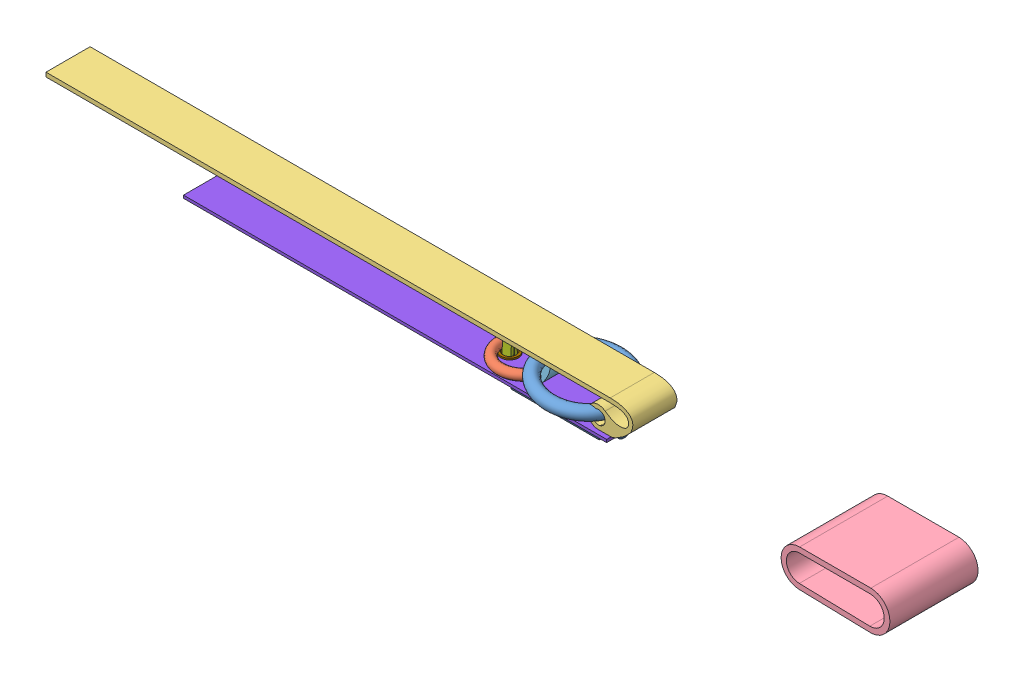
SolidWorks assembly 3-ring_assy_V1, configuration Default. Lengths in mm.
Overall size (289.62 40.67 53.79).
11 component instances, 10 part files, 25 mates.
Components (placement in the parent):
- H3860S_NO3_Ring-1: H3860S_NO3_Ring [Default] at (-68.6501 18.5376 22.2389) x (0 0 1) z (0.105483 0.994421 0) size (31.35 31.35 4.56)
- H3880S_NO4_Ring-1: H3880S_NO4_Ring [Default] at (-95.1677 16.38 22.2389) x (0 0 1) z (0 1 0) size (20.24 20.24 3.37)
- Webbing_mid-1: Webbing_mid [Default] at (-166.1457 26.6928 22.2389) x (1 0 0) z (0 0 -1) size (211.94 13.13 15.88)
- Webbing_main-1: Webbing_main [Default] x (-1 0 0) z (0 0 1) size (39.18 13.97 31.75)
- webbing_top_V1-2: webbing_top_V1 [Default] at (-133.3238 25.1688 22.2389) x (1 0 0) z (0 0 -1) size (81.41 11.51 12.7)
- yellow_cord_V1-1: yellow_cord_V1 [Default] at (-76.9625 11.3625 21.1309) x (0.034899 0 0.999391) z (0 -1 0) size (9.91 63.2 1.27)
- nylon_loop_V1-1: nylon_loop_V1 [Default] at (-108.6932 9.4219 22.2389) x (0 0 1) z (0 -1 0) size (3.01 25.4 13.88)
- grommet_assy-1: grommet_assy [Default] at (-244.1415 185.836 43.4745) x (0 0 -1) z (0 -1 0) size (19.05 152.4 6.48)
  - webbing_grommet_V1-1: webbing_grommet_V1 [Default] at (21.2356 27.4983 171.1427) size (19.05 152.4 1.02)
  - grommet_V1-1: grommet_V1 [Default] at (21.2356 135.4483 170.5712) x (1 0 0) z (0 -1 0) size (10.16 2.6 10.16)
  - yellow_cord_guide-1: yellow_cord_guide [Default] at (21.2356 176.7233 174.1907) x (1 0 0) z (0 -1 0) size (18.04 4.89 31.75)
Mates (geometry in assembly coordinates):
- Coincident65: coincident: plane of Webbing_main-1 through (0 0 0) normal (0 0 1); plane of assembly through (0 0 0) normal (0 0 1)
- Coincident66: coincident: plane of Webbing_main-1 through (0 0 0) normal (-1 0 0); plane of assembly through (0 0 0) normal (1 0 0)
- Coincident67: coincident: plane of Webbing_main-1 through (0 0 0) normal (0 -1 0); plane of assembly through (0 0 0) normal (0 1 0)
- Parallel29: parallel: plane of Webbing_mid-1 through (-166.1457 26.6928 22.2389) normal (0 1 0); plane of Webbing_main-1 through (0 0 0) normal (0 1 0)
- Parallel30: parallel: plane of Webbing_mid-1 through (-166.1457 26.6928 22.2389) normal (0 0 -1); plane of assembly through (0 0 0) normal (0 0 1)
- Coincident83: coincident: plane of Webbing_mid-1 through (-166.1457 25.1688 22.2389) normal (0 -1 0); plane of webbing_top_V1-2 through (-133.3238 25.1688 22.2389) normal (0 1 0)
- Parallel31: parallel: plane of Webbing_mid-1 through (-267.7457 25.1688 30.1764) normal (0 0 1); plane of webbing_top_V1-2 through (-171.4238 24.1528 28.5889) normal (0 0 1)
- Tangent33: tangent: torus of H3880S_NO4_Ring-1; plane of webbing_top_V1-2 through (-123.1879 -1.7048 0.0803) normal (0 -1 0)
- Angle1: planar angle = 0.034907 rad: cylinder of yellow_cord_V1-1 through (-127.7316 11.3625 22.9038) axis (0.999391 0 -0.034899) radius 0.635; cylinder of nylon_loop_V1-1 through (-107.1057 11.7068 22.2389) axis (-1 0 0) radius 0.762
- Parallel32: parallel: plane of H3880S_NO4_Ring-1 through (-95.1677 16.38 22.2389) normal (0 1 0); plane of assembly through (0 0 0) normal (0 1 0)
- Tangent35: tangent: torus of H3880S_NO4_Ring-1; cylinder of webbing_top_V1-2 through (-95.2238 16.5328 15.8889) axis (0 0 1) radius 1.524
- Tangent37: tangent: torus of H3860S_NO3_Ring-1; cylinder of webbing_top_V1-2 through (-95.2238 21.6128 15.8889) axis (0 0 1) radius 2.54
- Coincident84: coincident: plane of H3880S_NO4_Ring-1 through (-95.1677 16.38 22.2389) normal (0 0 1); plane of webbing_top_V1-2 through (-133.3238 25.1688 22.2389) normal (0 0 -1)
- Coincident85: coincident: plane of Webbing_mid-1 through (-166.1457 26.6928 22.2389) normal (0 0 -1); plane of webbing_top_V1-2 through (-133.3238 25.1688 22.2389) normal (0 0 -1)
- Coincident86: coincident: plane of H3860S_NO3_Ring-1 through (-68.6501 18.5376 22.2389) normal (0 0 1); plane of H3880S_NO4_Ring-1 through (-95.1677 16.38 22.2389) normal (0 0 1)
- Tangent38: tangent: torus of H3860S_NO3_Ring-1; cylinder of Webbing_mid-1 through (-68.7807 18.5474 30.1764) axis (0 0 -1) radius 2.413
- Parallel34: parallel: plane of webbing_top_V1-2 through (-133.3238 24.1528 22.2389) normal (0 -1 0); plane of grommet_assy-1/webbing_grommet_V1-1 through (-194.8149 13.6773 19.4353) normal (0 -1 0)
- Coincident91: coincident: plane of webbing_top_V1-2 through (-133.3238 24.1528 22.2389) normal (0 -1 0); plane of nylon_loop_V1-1 through (-108.6932 24.1528 23.1347) normal (0 1 0)
- Coincident92: coincident: plane of Webbing_mid-1 through (-166.1457 26.6928 22.2389) normal (0 0 -1); plane of nylon_loop_V1-1 through (-108.6932 9.4219 22.2389) normal (0 0 1)
- Coincident93: coincident: plane of H3880S_NO4_Ring-1 through (-110.2807 16.38 22.2389) normal (1 0 0); plane of nylon_loop_V1-1 through (-110.2807 9.4219 22.2389) normal (-1 0 0)
- Coincident95: coincident: line of yellow_cord_V1-1 through (-127.7316 11.3625 22.9038) axis (0.999391 0 -0.034899); point of nylon_loop_V1-1
- Distance1: distance = 31.75 mm: point of nylon_loop_V1-1; plane of yellow_cord_V1-1 through (-76.9625 11.3625 21.1309) normal (0.999391 0 -0.034899)
- Parallel35: parallel: plane of webbing_top_V1-2 through (-133.3238 24.1528 22.2389) normal (0 -1 0); plane of yellow_cord_V1-1 through (-76.9625 10.7275 21.1309) normal (0 -1 0)
- Concentric6: concentric: line of nylon_loop_V1-1 through (-108.6932 11.4539 22.2389) axis (0 -1 0); cylinder of grommet_assy-1/grommet_V1-1 through (-108.6932 13.6773 22.2389) axis (0 1 0) radius 2.3813
- Tangent41: tangent: torus of H3880S_NO4_Ring-1; plane of grommet_assy-1/webbing_grommet_V1-1 through (-216.6432 14.6933 22.2389) normal (0 1 0)
